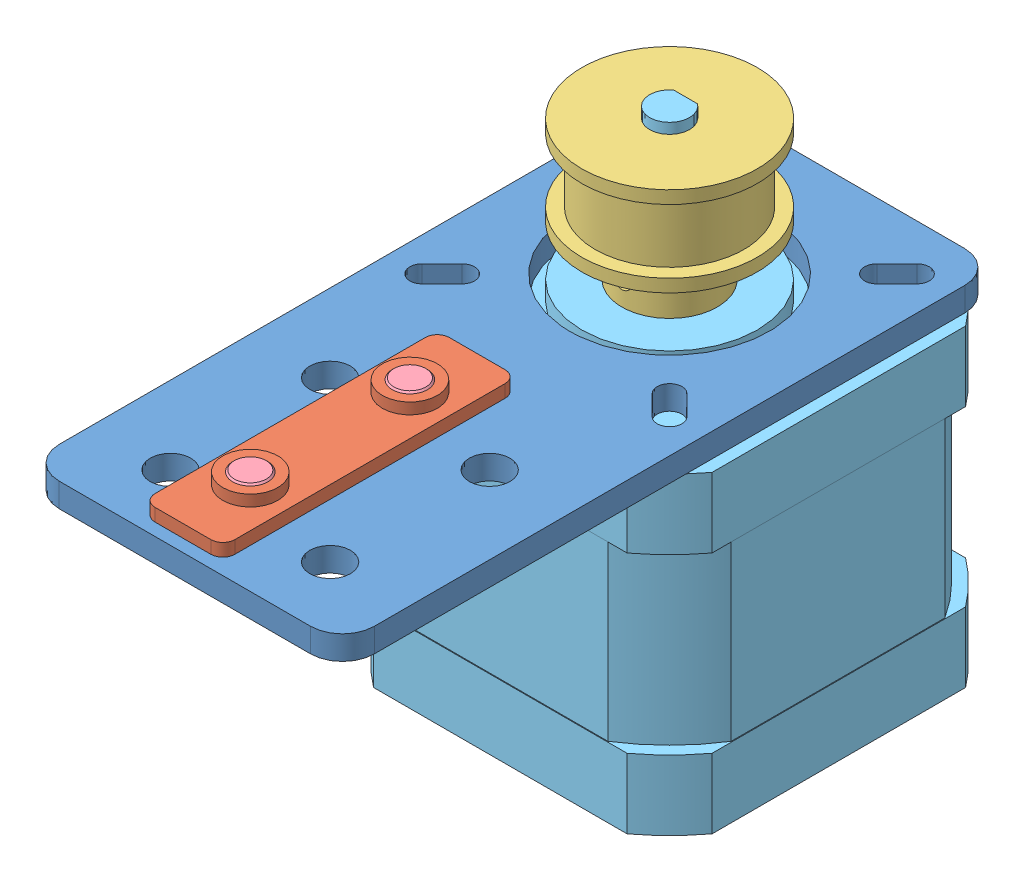
SolidWorks assembly MOTOR_MOUNT_2, configuration Default. Lengths in mm.
Overall size (42.42 60.45 82.24).
6 component instances, 5 part files, 12 mates.
Components (placement in the parent):
- Motor Mount Plate Nema 17-1: Motor Mount Plate Nema 17 [Default] at (36.577 37.551 42.5841) size (39.5 3 82)
- Double Tee Nut-1: Double Tee Nut [Default] at (41.577 42.351 103.5741) x (0 0 -1) z (0 1 0) size (36.88 10 3)
- GT2 Timing Pulley 30 Tooth-1: GT2 Timing Pulley 30 Tooth [Default] at (36.577 39.951 42.5841) x (0 1 0) z (0 0 1) size (17.5 22 22)
- LP_SH_SCREW_M5_8mm-1: LP_SH_SCREW_M5_8mm [M5 x 8] at (36.577 45.551 75.1341) x (0 1 0) z (0 0 1) size (9.62 9 9)
- LP_SH_SCREW_M5_8mm-2: LP_SH_SCREW_M5_8mm [M5 x 8] at (36.577 45.551 95.1341) x (0 1 0) z (0 0 1) size (9.62 9 9)
- NEMA_17_MOTOR-1: NEMA_17_MOTOR [Default] at (36.577 37.551 42.5841) x (1 0 0) z (0 1 0) size (42.42 42.42 60.45)
Mates (geometry in assembly coordinates):
- Concentric1: concentric anti-aligned: cylinder of Motor Mount Plate Nema 17-1 through (36.577 40.551 75.1341) axis (0 -1 0) radius 2.55; cylinder of Double Tee Nut-1 through (36.577 45.351 75.1341) axis (0 1 0) radius 2.1
- Concentric2: concentric anti-aligned: cylinder of Motor Mount Plate Nema 17-1 through (36.577 40.551 95.1341) axis (0 -1 0) radius 2.55; cylinder of Double Tee Nut-1 through (36.577 45.351 95.1341) axis (0 1 0) radius 2.1
- Distance2: distance = 1.8 mm anti-aligned: plane of Double Tee Nut-1 through (33.077 42.351 68.1941) normal (0 -1 0); plane of Motor Mount Plate Nema 17-1 through (20.827 40.551 99.3341) normal (0 1 0)
- Concentric81: concentric anti-aligned: cylinder of Motor Mount Plate Nema 17-1 through (36.577 40.551 75.1341) axis (0 -1 0) radius 2.55; cylinder of LP_SH_SCREW_M5_8mm-1 through (36.577 37.551 75.1341) axis (0 1 0) radius 2.5
- Coincident101: coincident anti-aligned: plane of Motor Mount Plate Nema 17-1 through (20.827 37.551 99.3341) normal (0 -1 0); plane of LP_SH_SCREW_M5_8mm-1 through (32.4156 37.551 75.1341) normal (0 1 0)
- Concentric91: concentric anti-aligned: cylinder of Motor Mount Plate Nema 17-1 through (36.577 40.551 95.1341) axis (0 -1 0) radius 2.55; cylinder of LP_SH_SCREW_M5_8mm-2 through (36.577 37.551 95.1341) axis (0 1 0) radius 2.5
- Coincident111: coincident anti-aligned: plane of Motor Mount Plate Nema 17-1 through (20.827 37.551 99.3341) normal (0 -1 0); plane of LP_SH_SCREW_M5_8mm-2 through (32.4156 37.551 95.1341) normal (0 1 0)
- Concentric92: concentric aligned: cylinder of Motor Mount Plate Nema 17-1 through (36.577 40.551 42.5841) axis (0 -1 0) radius 12.5; cylinder of NEMA_17_MOTOR-1 through (36.577 39.951 42.5841) axis (0 -1 0) radius 11
- Coincident112: coincident anti-aligned: plane of Motor Mount Plate Nema 17-1 through (20.827 37.551 99.3341) normal (0 -1 0); plane of NEMA_17_MOTOR-1 through (36.577 37.551 42.5841) normal (0 1 0)
- Parallel1: parallel aligned: plane of Motor Mount Plate Nema 17-1 through (56.327 40.551 99.3341) normal (1 0 0); plane of NEMA_17_MOTOR-1 through (57.786 -1.689 63.7931) normal (1 0 0)
- Concentric93: concentric anti-aligned: cylinder of GT2 Timing Pulley 30 Tooth-1 through (36.577 39.951 42.5841) axis (0 1 0) radius 2.5; cylinder of NEMA_17_MOTOR-1 through (36.577 58.761 42.5841) axis (0 -1 0) radius 2.5
- Coincident113: coincident anti-aligned: plane of GT2 Timing Pulley 30 Tooth-1 through (34.077 39.951 42.5841) normal (0 -1 0); plane of NEMA_17_MOTOR-1 through (36.577 39.951 42.5841) normal (0 1 0)
